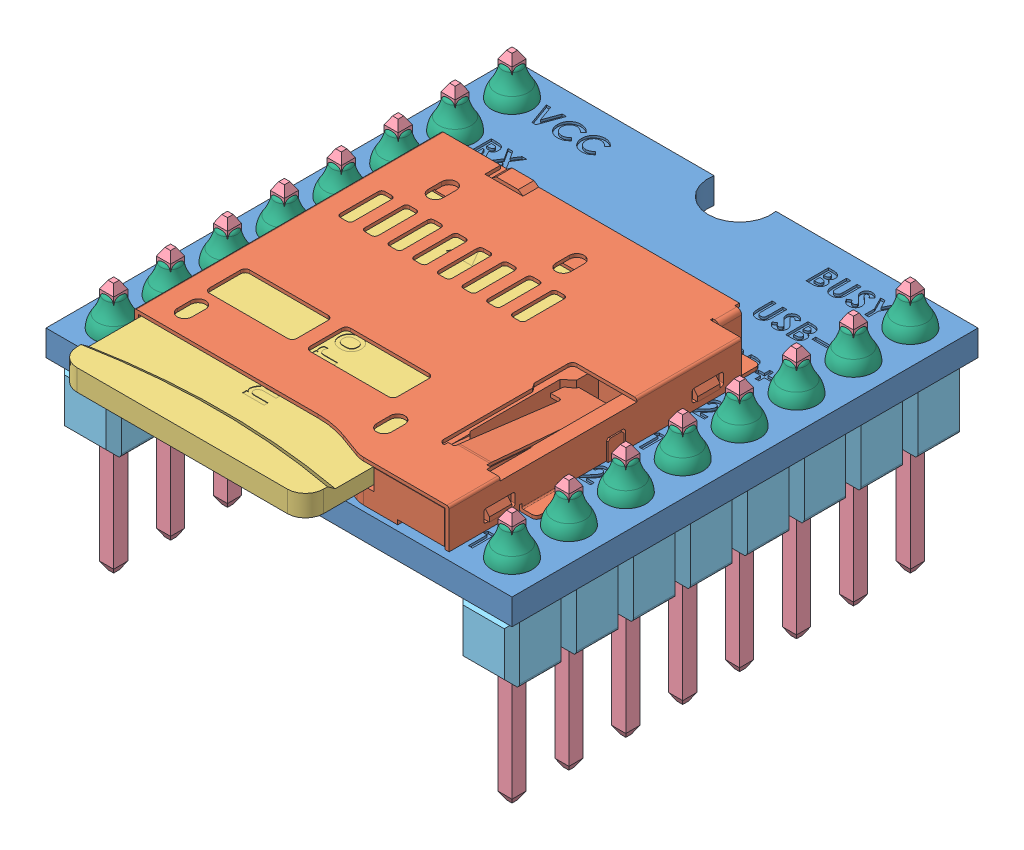
SolidWorks assembly DFPlayer Mini, configuration Default. Lengths in mm.
Overall size (20.8 11.2 23.46).
68 component instances, 6 part files, 0 mates.
Components (placement in the parent):
- DFPlayer Mini PCB-1: DFPlayer Mini PCB [Default] at origin size (20.8 1.15 20.8)
- SD card Assem-1: SD card Assem [Default] at (-198.0203 122.5536 -43.8714) x (0 1 0) z (1 0 0) size (2.44 17.9 16)
  - CD card slot-1: CD card slot [Default] at (-120.5536 47.0914 197.6703) x (0 0 1) z (1 0 0) size (16 15 2.44)
  - Micro sd card-1: Micro sd card [Default] at (-120.5536 45.5089 151.9853) x (0 0 1) z (1 0 0) size (11 15 0.95)
- DFPlayer Mini Pin-1: DFPlayer Mini Pin [Default] at (8.89 0 8.89) x (0 0 -1) z (0 -1 0) size (2.54 2.54 11.2)
  - 11_20mm pin-1: 11_20mm pin [Default] at (0 0 2.6) size (0.63 0.63 11.2)
  - Pin Header 1x12 TH Pitch 2-1: Pin Header 1x12 TH Pitch 2 [Default] at (-27.94 0 -0.0014) size (2.54 2.54 2.8)
  - solder-1: solder [Default] at (0 0 -1.15) x (1 0 0) z (0 1 0) size (1.8 1.45 1.8)
- DFPlayer Mini Pin-2: DFPlayer Mini Pin [Default] at (-8.89 0 8.89) x (0 0 1) z (0 -1 0) size (2.54 2.54 11.2)
  - 11_20mm pin-1: 11_20mm pin [Default] at (0 0 2.6) size (0.63 0.63 11.2)
  - Pin Header 1x12 TH Pitch 2-1: Pin Header 1x12 TH Pitch 2 [Default] at (-27.94 0 -0.0014) size (2.54 2.54 2.8)
  - solder-1: solder [Default] at (0 0 -1.15) x (1 0 0) z (0 1 0) size (1.8 1.45 1.8)
- DFPlayer Mini Pin-3: DFPlayer Mini Pin [Default] at (-8.89 0 6.35) x (0 0 1) z (0 -1 0) size (2.54 2.54 11.2)
  - 11_20mm pin-1: 11_20mm pin [Default] at (0 0 2.6) size (0.63 0.63 11.2)
  - Pin Header 1x12 TH Pitch 2-1: Pin Header 1x12 TH Pitch 2 [Default] at (-27.94 0 -0.0014) size (2.54 2.54 2.8)
  - solder-1: solder [Default] at (0 0 -1.15) x (1 0 0) z (0 1 0) size (1.8 1.45 1.8)
- DFPlayer Mini Pin-4: DFPlayer Mini Pin [Default] at (-8.89 0 3.81) x (0 0 1) z (0 -1 0) size (2.54 2.54 11.2)
  - 11_20mm pin-1: 11_20mm pin [Default] at (0 0 2.6) size (0.63 0.63 11.2)
  - Pin Header 1x12 TH Pitch 2-1: Pin Header 1x12 TH Pitch 2 [Default] at (-27.94 0 -0.0014) size (2.54 2.54 2.8)
  - solder-1: solder [Default] at (0 0 -1.15) x (1 0 0) z (0 1 0) size (1.8 1.45 1.8)
- DFPlayer Mini Pin-5: DFPlayer Mini Pin [Default] at (-8.89 0 1.27) x (0 0 1) z (0 -1 0) size (2.54 2.54 11.2)
  - 11_20mm pin-1: 11_20mm pin [Default] at (0 0 2.6) size (0.63 0.63 11.2)
  - Pin Header 1x12 TH Pitch 2-1: Pin Header 1x12 TH Pitch 2 [Default] at (-27.94 0 -0.0014) size (2.54 2.54 2.8)
  - solder-1: solder [Default] at (0 0 -1.15) x (1 0 0) z (0 1 0) size (1.8 1.45 1.8)
- DFPlayer Mini Pin-6: DFPlayer Mini Pin [Default] at (-8.89 0 -1.27) x (0 0 1) z (0 -1 0) size (2.54 2.54 11.2)
  - 11_20mm pin-1: 11_20mm pin [Default] at (0 0 2.6) size (0.63 0.63 11.2)
  - Pin Header 1x12 TH Pitch 2-1: Pin Header 1x12 TH Pitch 2 [Default] at (-27.94 0 -0.0014) size (2.54 2.54 2.8)
  - solder-1: solder [Default] at (0 0 -1.15) x (1 0 0) z (0 1 0) size (1.8 1.45 1.8)
- DFPlayer Mini Pin-7: DFPlayer Mini Pin [Default] at (-8.89 0 -3.81) x (0 0 1) z (0 -1 0) size (2.54 2.54 11.2)
  - 11_20mm pin-1: 11_20mm pin [Default] at (0 0 2.6) size (0.63 0.63 11.2)
  - Pin Header 1x12 TH Pitch 2-1: Pin Header 1x12 TH Pitch 2 [Default] at (-27.94 0 -0.0014) size (2.54 2.54 2.8)
  - solder-1: solder [Default] at (0 0 -1.15) x (1 0 0) z (0 1 0) size (1.8 1.45 1.8)
- DFPlayer Mini Pin-8: DFPlayer Mini Pin [Default] at (-8.89 0 -6.35) x (0 0 1) z (0 -1 0) size (2.54 2.54 11.2)
  - 11_20mm pin-1: 11_20mm pin [Default] at (0 0 2.6) size (0.63 0.63 11.2)
  - Pin Header 1x12 TH Pitch 2-1: Pin Header 1x12 TH Pitch 2 [Default] at (-27.94 0 -0.0014) size (2.54 2.54 2.8)
  - solder-1: solder [Default] at (0 0 -1.15) x (1 0 0) z (0 1 0) size (1.8 1.45 1.8)
- DFPlayer Mini Pin-9: DFPlayer Mini Pin [Default] at (-8.89 0 -8.89) x (0 0 1) z (0 -1 0) size (2.54 2.54 11.2)
  - 11_20mm pin-1: 11_20mm pin [Default] at (0 0 2.6) size (0.63 0.63 11.2)
  - Pin Header 1x12 TH Pitch 2-1: Pin Header 1x12 TH Pitch 2 [Default] at (-27.94 0 -0.0014) size (2.54 2.54 2.8)
  - solder-1: solder [Default] at (0 0 -1.15) x (1 0 0) z (0 1 0) size (1.8 1.45 1.8)
- DFPlayer Mini Pin-10: DFPlayer Mini Pin [Default] at (8.89 0 6.35) x (0 0 -1) z (0 -1 0) size (2.54 2.54 11.2)
  - 11_20mm pin-1: 11_20mm pin [Default] at (0 0 2.6) size (0.63 0.63 11.2)
  - Pin Header 1x12 TH Pitch 2-1: Pin Header 1x12 TH Pitch 2 [Default] at (-27.94 0 -0.0014) size (2.54 2.54 2.8)
  - solder-1: solder [Default] at (0 0 -1.15) x (1 0 0) z (0 1 0) size (1.8 1.45 1.8)
- DFPlayer Mini Pin-11: DFPlayer Mini Pin [Default] at (8.89 0 3.81) x (0 0 -1) z (0 -1 0) size (2.54 2.54 11.2)
  - 11_20mm pin-1: 11_20mm pin [Default] at (0 0 2.6) size (0.63 0.63 11.2)
  - Pin Header 1x12 TH Pitch 2-1: Pin Header 1x12 TH Pitch 2 [Default] at (-27.94 0 -0.0014) size (2.54 2.54 2.8)
  - solder-1: solder [Default] at (0 0 -1.15) x (1 0 0) z (0 1 0) size (1.8 1.45 1.8)
- DFPlayer Mini Pin-12: DFPlayer Mini Pin [Default] at (8.89 0 1.27) x (0 0 -1) z (0 -1 0) size (2.54 2.54 11.2)
  - 11_20mm pin-1: 11_20mm pin [Default] at (0 0 2.6) size (0.63 0.63 11.2)
  - Pin Header 1x12 TH Pitch 2-1: Pin Header 1x12 TH Pitch 2 [Default] at (-27.94 0 -0.0014) size (2.54 2.54 2.8)
  - solder-1: solder [Default] at (0 0 -1.15) x (1 0 0) z (0 1 0) size (1.8 1.45 1.8)
- DFPlayer Mini Pin-13: DFPlayer Mini Pin [Default] at (8.89 0 -1.27) x (0 0 -1) z (0 -1 0) size (2.54 2.54 11.2)
  - 11_20mm pin-1: 11_20mm pin [Default] at (0 0 2.6) size (0.63 0.63 11.2)
  - Pin Header 1x12 TH Pitch 2-1: Pin Header 1x12 TH Pitch 2 [Default] at (-27.94 0 -0.0014) size (2.54 2.54 2.8)
  - solder-1: solder [Default] at (0 0 -1.15) x (1 0 0) z (0 1 0) size (1.8 1.45 1.8)
- DFPlayer Mini Pin-14: DFPlayer Mini Pin [Default] at (8.89 0 -3.81) x (0 0 -1) z (0 -1 0) size (2.54 2.54 11.2)
  - 11_20mm pin-1: 11_20mm pin [Default] at (0 0 2.6) size (0.63 0.63 11.2)
  - Pin Header 1x12 TH Pitch 2-1: Pin Header 1x12 TH Pitch 2 [Default] at (-27.94 0 -0.0014) size (2.54 2.54 2.8)
  - solder-1: solder [Default] at (0 0 -1.15) x (1 0 0) z (0 1 0) size (1.8 1.45 1.8)
- DFPlayer Mini Pin-15: DFPlayer Mini Pin [Default] at (8.89 0 -6.35) x (0 0 -1) z (0 -1 0) size (2.54 2.54 11.2)
  - 11_20mm pin-1: 11_20mm pin [Default] at (0 0 2.6) size (0.63 0.63 11.2)
  - Pin Header 1x12 TH Pitch 2-1: Pin Header 1x12 TH Pitch 2 [Default] at (-27.94 0 -0.0014) size (2.54 2.54 2.8)
  - solder-1: solder [Default] at (0 0 -1.15) x (1 0 0) z (0 1 0) size (1.8 1.45 1.8)
- DFPlayer Mini Pin-16: DFPlayer Mini Pin [Default] at (8.89 0 -8.89) x (0 0 -1) z (0 -1 0) size (2.54 2.54 11.2)
  - 11_20mm pin-1: 11_20mm pin [Default] at (0 0 2.6) size (0.63 0.63 11.2)
  - Pin Header 1x12 TH Pitch 2-1: Pin Header 1x12 TH Pitch 2 [Default] at (-27.94 0 -0.0014) size (2.54 2.54 2.8)
  - solder-1: solder [Default] at (0 0 -1.15) x (1 0 0) z (0 1 0) size (1.8 1.45 1.8)
